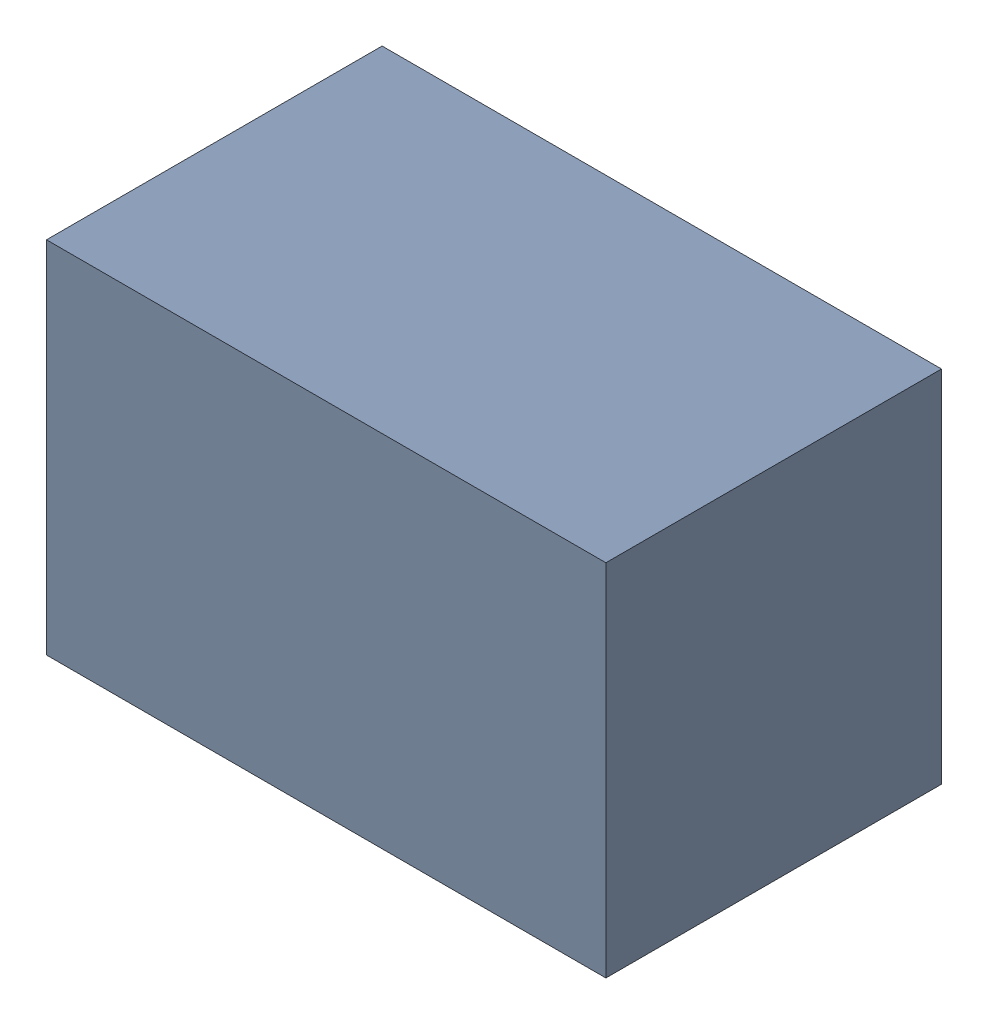
SolidWorks assembly C13, configuration Default. Lengths in mm.
Overall size (2.1 1.35 1.26).
2 component instances, 1 part files, 0 mates.
Components (placement in the parent):
- 407985824-1: 407985824 [Default] at (60.071 63.246 0.0127) size (2.1 1.35 1.26)
  - Extruded_2-1: Extruded_2 [Default] at origin size (2.1 1.35 1.26)
